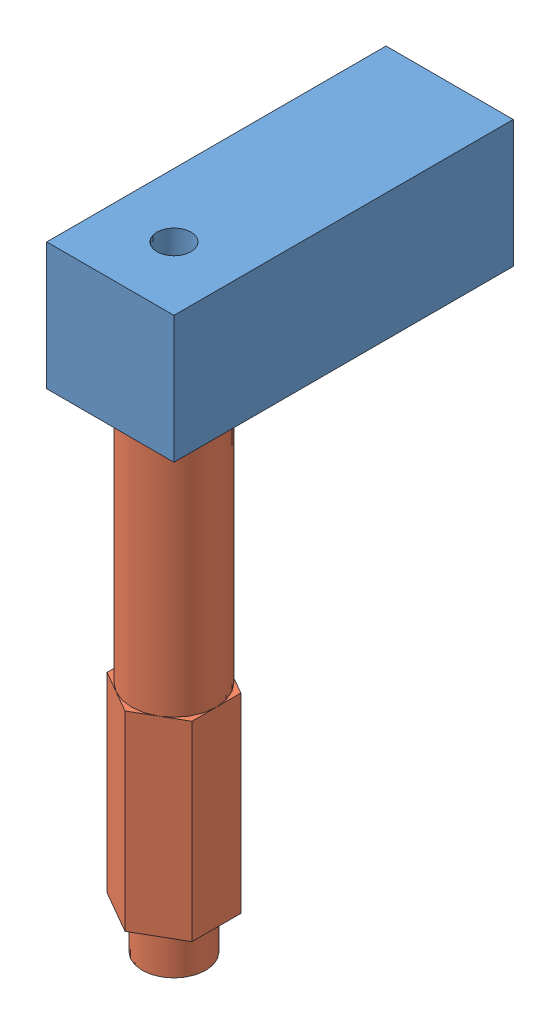
SolidWorks assembly AlternativeShaftTest, configuration Default. Lengths in mm.
Overall size (19.05 92.08 50.8).
2 component instances, 2 part files, 3 mates.
Components (placement in the parent):
- AlternativeMBCoupler-1: AlternativeMBCoupler [Default] at origin size (19.05 19.05 50.8)
- MoveableBallast_OutputShaft-1: MoveableBallast_OutputShaft [AlternativeShaft] at (0 -76.2 41.275) size (12.7 85.72 14.66)
Mates (geometry in assembly coordinates):
- Concentric1: concentric anti-aligned: cylinder of AlternativeMBCoupler-1 through (0 3.175 41.275) axis (0 -1 0) radius 2.5527; cylinder of MoveableBallast_OutputShaft-1 through (0 3.175 41.275) axis (0 1 0) radius 2.0193
- Coincident1: coincident anti-aligned: plane of AlternativeMBCoupler-1 through (3.9688 3.175 44.45) normal (-1 0 0); plane of MoveableBallast_OutputShaft-1 through (3.9688 -9.525 41.275) normal (1 0 0)
- Coincident2: coincident anti-aligned: plane of AlternativeMBCoupler-1 through (-0.7937 3.175 44.45) normal (0 -1 0); plane of MoveableBallast_OutputShaft-1 through (0 3.175 41.275) normal (0 1 0)
